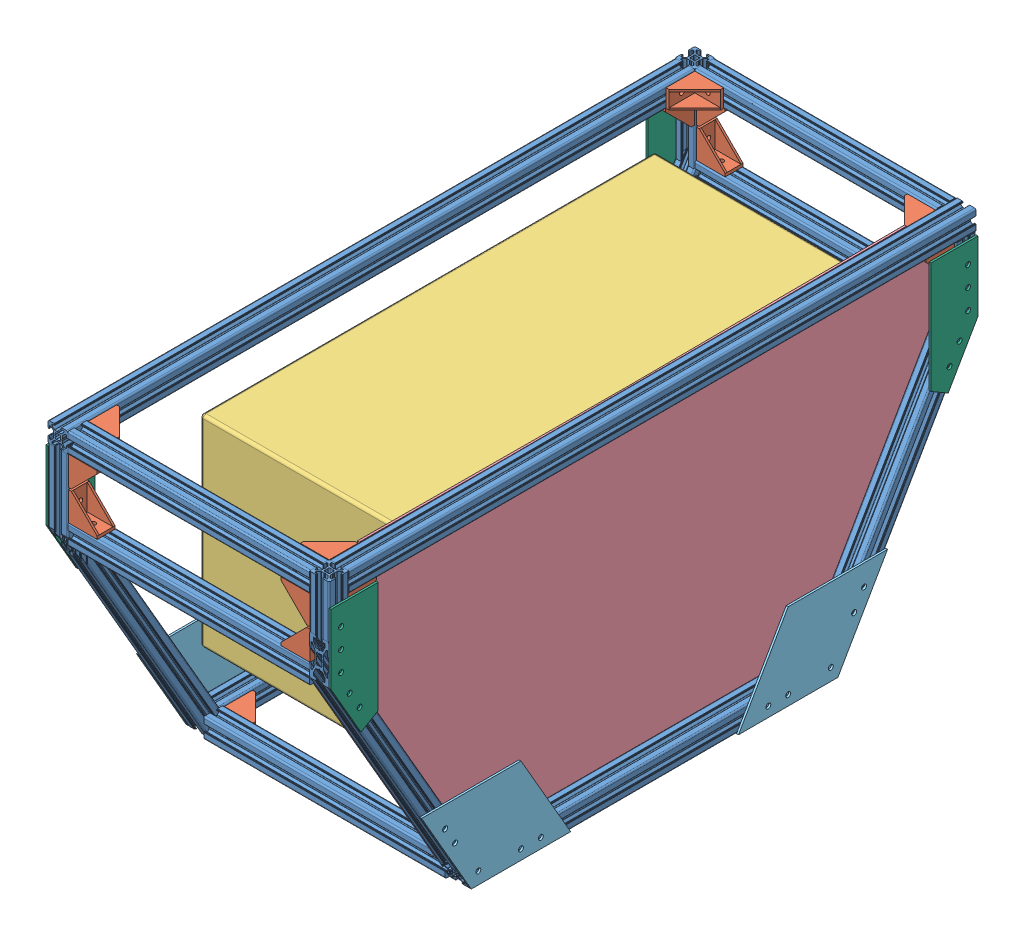
SolidWorks assembly FC, configuration Default. Lengths in mm.
Overall size (287 385.78 744.01).
43 component instances, 9 part files, 122 mates.
Components (placement in the parent):
- Front Compartment Chassis-1: Front Compartment Chassis [Default<As Machined>] at (339.5187 321.3389 505.6666) size (283 336.94 651)
- L- Bracket-1: L- Bracket [Default] at (86.5177 199.1423 674.3681) x (0 1 0) z (-1 0 0) size (18 29 29)
- L- Bracket-2: L- Bracket [Default] at (86.5177 200.1436 336.9668) x (0 -1 0) z (-1 0 0) size (18 29 29)
- L- Bracket-3: L- Bracket [Default] at (329.5198 200.1418 336.9668) x (0 -1 0) z (0 0 -1) size (18 29 29)
- L- Bracket-4: L- Bracket [Default] at (329.5198 200.1418 674.3681) x (0 1 0) z (0 0 1) size (18 29 29)
- L- Bracket-5: L- Bracket [Default] at (86.5177 446.5855 189.6668) x (0 0 1) z (-1 0 0) size (18 29 29)
- L- Bracket-6: L- Bracket [Default] at (329.5198 446.5855 189.6668) x (0 0 -1) z (1 0 0) size (18 29 29)
- L- Bracket-7: L- Bracket [Default] at (86.5177 446.5855 821.6663) x (0 0 1) z (-1 0 0) size (18 29 29)
- L- Bracket-8: L- Bracket [Default] at (329.5198 446.5855 821.6681) x (0 0 -1) z (1 0 0) size (18 29 29)
- L- Bracket-9: L- Bracket [Default] at (329.5198 506.5877 821.6681) x (0 0 -1) z (0 1 0) size (18 29 29)
- L- Bracket-10: L- Bracket [Default] at (86.5177 506.5877 189.6668) x (0 0 1) z (0 1 0) size (18 29 29)
- L- Bracket-11: L- Bracket [Default] at (339.0177 506.5881 200.165) x (1 0 0) z (0 0 -1) size (18 29 29)
- L- Bracket-12: L- Bracket [Default] at (329.5198 517.0877 811.1681) x (0 1 0) z (0 0 1) size (18 29 29)
- L- Bracket-13: L- Bracket [Default] at (339.0177 506.5881 811.1681) x (1 0 0) z (0 1 0) size (18 29 29)
- L- Bracket-14: L- Bracket [Default] at (329.5198 516.0868 200.1668) x (0 1 0) z (1 0 0) size (18 29 29)
- L- Bracket-15: L- Bracket [Default] at (329.5198 506.5877 189.665) x (0 0 -1) z (0 1 0) size (18 29 29)
- L- Bracket-16: L- Bracket [Default] at (86.5177 516.0855 200.1668) x (0 1 0) z (0 0 -1) size (18 29 29)
- L- Bracket-18: L- Bracket [Default] at (86.5177 516.0855 811.1681) x (0 -1 0) z (0 0 1) size (18 29 29)
- L- Bracket-19: L- Bracket [Default] at (86.5177 506.5877 821.6663) x (0 0 -1) z (-1 0 0) size (18 29 29)
- L- Bracket-20: L- Bracket [Default] at (76.0177 506.5864 811.1663) x (-1 0 0) z (0 0 1) size (18 29 29)
- L- Bracket-23: L- Bracket [Default] at (77.0198 506.5864 200.1668) x (-1 0 0) z (0 1 0) size (18 29 29)
- Payload-2: Payload [Default] at (327.5198 411.615 507.0924) x (0 0 1) z (-1 0 0) size (457.2 208.2 208.2)
- FC Base-1: FC Base [Default] at (327.5198 -0.0183 1010.7565) x (0 0 -1) z (1 0 0) size (639.15 336.88 2)
- FC Shear Plate 2-1: FC Shear Plate 2 [Default] at (64.5198 189.7281 590.188) x (0 0.779319 0.626628) z (1 0 0) size (161.49 93.23 2)
- FC Shear Plate 2-2: FC Shear Plate 2 [Default] at (64.5198 276.2461 272.0032) x (0 -0.153016 0.988224) z (1 0 0) size (161.49 93.23 2)
- FC Shear Plate 2-3: FC Shear Plate 2 [Default] at (349.5177 189.6418 590.1402) x (0 0.779319 0.626628) z (1 0 0) size (161.49 93.23 2)
- FC Shear Plate 2-4: FC Shear Plate 2 [Default] at (351.5177 189.6418 421.1929) x (0 0.779319 -0.626628) z (-1 0 0) size (161.49 93.23 2)
- FC Shear Plate 1-4: FC Shear Plate 1 [Default] at (351.5177 443.907 812.5065) x (0 0.533782 0.845622) z (-1 0 0) size (99.78 112.38 2)
- FC Shear Plate 1-5: FC Shear Plate 1 [Default] at (349.5177 443.907 198.8266) x (0 0.533782 -0.845622) z (1 0 0) size (99.78 112.38 2)
- FC Shear Plate 1-6: FC Shear Plate 1 [Default] at (64.5198 443.9075 198.8283) x (0 0.533782 -0.845622) z (1 0 0) size (99.78 112.38 2)
- FC Shear Plate 1-7: FC Shear Plate 1 [Default] at (66.5198 443.9075 812.5048) x (0 0.533782 0.845622) z (-1 0 0) size (99.78 112.38 2)
- L- Bracket-24: L- Bracket [Default] at (327.5198 418.1739 278.4924) x (0 1 0) z (0 0 1) size (18 29 29)
- L- Bracket-25: L- Bracket [Default] at (327.5198 423.1136 735.6924) x (0 -1 0) z (0 0 -1) size (18 29 29)
- L- Bracket-26: L- Bracket [Default] at (327.5198 310.015 506.1761) x (0 0 -1) z (0 1 0) size (18 29 29)
- Assem1-1: Assem1 [Default] at (297.6727 207.8891 498.6482) x (0 -1 0) z (-1 0 0) (suppressed, hidden)
- l small plate-1: l small plate [Default] at (191.63 189.6407 546.568) x (0 1 0) z (-1 0 0) (suppressed, hidden)
- l small plate-3: l small plate [Default] at (191.63 209.6407 462.5667) x (0 -1 0) z (-1 0 0) (suppressed, hidden)
- big bolt-1: big bolt [Default] at (185.63 199.6407 536.568) x (0 0 -1) z (1 0 0) (suppressed, hidden)
- l small plate-4: l small plate [Default] at (257.6584 209.6429 546.568) x (0 -1 0) z (1 0 0) (suppressed, hidden)
- big bolt-2: big bolt [Default] at (185.63 199.6407 472.5667) x (0 0 -1) z (1 0 0) (suppressed, hidden)
- l small plate-5: l small plate [Default] at (257.6584 189.6429 462.5667) x (0 1 0) z (1 0 0) (suppressed, hidden)
- nut-1: nut [Default] at (198.9295 199.6429 472.5667) x (0 -0.681517 0.731802) z (-1 0 0) (suppressed, hidden)
- nut-2: nut [Default] at (204.9354 199.6429 536.568) x (0 -0.369959 0.929048) z (-1 0 0) (suppressed, hidden)
Mates (geometry in assembly coordinates):
- Coincident386: coincident: plane of assembly; plane of assembly; plane of Front Compartment Chassis-1 through (86.5177 321.3389 505.6666) normal (1 0 0); plane of L- Bracket-1 through (86.5177 190.1423 645.3681) normal (-1 0 0)
- Coincident387: coincident: plane of assembly; plane of assembly; plane of Front Compartment Chassis-1 through (76.5187 208.141 674.3681) normal (0 0 -1); plane of L- Bracket-1 through (86.5177 190.1423 674.3681) normal (0 0 1)
- Coincident388: coincident: line of assembly; line of assembly; line of Front Compartment Chassis-1 through (86.5177 208.1423 310.5137) axis (0 0 1); line of L- Bracket-1 through (86.5177 208.1423 645.3681) axis (0 0 1)
- Coincident389: coincident: plane of assembly; plane of assembly; plane of Front Compartment Chassis-1 through (76.5187 208.141 674.3681) normal (0 0 -1); plane of L- Bracket-4 through (300.5198 191.1418 674.3681) normal (0 0 1)
- Coincident390: coincident: plane of assembly; plane of assembly; plane of Front Compartment Chassis-1 through (329.5198 195.8931 684.3666) normal (-1 0 0); plane of L- Bracket-4 through (329.5198 191.1418 674.3681) normal (1 0 0)
- Coincident391: coincident: line of assembly; line of assembly; line of Front Compartment Chassis-1 through (329.5198 191.1418 691.0062) axis (0 0 -1); line of L- Bracket-4 through (329.5198 191.1418 674.3681) axis (0 0 -1)
- Coincident392: coincident: plane of assembly; plane of assembly; plane of Front Compartment Chassis-1 through (329.5198 195.8931 684.3666) normal (-1 0 0); plane of L- Bracket-3 through (329.5198 209.1418 336.9668) normal (1 0 0)
- Coincident393: coincident: plane of assembly; plane of assembly; plane of Front Compartment Chassis-1 through (76.5187 191.1431 336.9668) normal (0 0 1); plane of L- Bracket-3 through (300.5198 209.1418 336.9668) normal (0 0 -1)
- Coincident394: coincident: line of assembly; line of assembly; line of Front Compartment Chassis-1 through (329.5198 191.1418 691.0062) axis (0 0 -1); line of L- Bracket-3 through (329.5198 191.1418 336.9668) axis (0 0 1)
- Coincident395: coincident: plane of assembly; plane of assembly; plane of Front Compartment Chassis-1 through (86.5177 321.3389 505.6666) normal (1 0 0); plane of L- Bracket-2 through (86.5177 209.1436 365.9668) normal (-1 0 0)
- Coincident396: coincident: plane of assembly; plane of assembly; plane of Front Compartment Chassis-1 through (76.5187 191.1431 336.9668) normal (0 0 1); plane of L- Bracket-2 through (86.5177 209.1436 336.9668) normal (0 0 -1)
- Coincident397: coincident: line of assembly; line of assembly; line of Front Compartment Chassis-1 through (86.5177 191.1436 667.9127) axis (0 0 -1); line of L- Bracket-2 through (86.5177 191.1436 365.9668) axis (0 0 -1)
- Coincident398: coincident: plane of assembly; plane of assembly; plane of Front Compartment Chassis-1 through (76.5187 446.5855 817.4176) normal (0 1 0); plane of L- Bracket-7 through (86.5177 446.5855 812.6663) normal (0 -1 0)
- Coincident399: coincident: plane of assembly; plane of assembly; plane of Front Compartment Chassis-1 through (86.5177 436.5866 812.6663) normal (1 0 0); plane of L- Bracket-7 through (86.5177 475.5855 812.6663) normal (-1 0 0)
- Coincident400: coincident: line of assembly; line of assembly; line of Front Compartment Chassis-1 through (86.5177 401.8668 812.6663) axis (0 1 0); line of L- Bracket-7 through (86.5177 475.5855 812.6663) axis (0 -1 0)
- Coincident401: coincident: plane of assembly; plane of assembly; plane of Front Compartment Chassis-1 through (76.5187 446.5855 817.4176) normal (0 1 0); plane of L- Bracket-8 through (329.5198 446.5855 830.6681) normal (0 -1 0)
- Coincident402: coincident: plane of assembly; plane of assembly; plane of Front Compartment Chassis-1 through (329.5198 516.5866 812.6681) normal (-1 0 0); plane of L- Bracket-8 through (329.5198 475.5855 830.6681) normal (1 0 0)
- Coincident403: coincident: line of assembly; line of assembly; line of Front Compartment Chassis-1 through (86.5177 446.5855 812.6681) axis (1 0 0); line of L- Bracket-8 through (329.5198 446.5855 812.6681) axis (-1 0 0)
- Coincident404: coincident: plane of assembly; plane of assembly; plane of Front Compartment Chassis-1 through (329.5198 516.5866 812.6681) normal (-1 0 0); plane of L- Bracket-9 through (329.5198 506.5877 830.6681) normal (1 0 0)
- Coincident405: coincident: plane of assembly; plane of assembly; plane of Front Compartment Chassis-1 through (76.5187 506.5877 812.6681) normal (0 -1 0); plane of L- Bracket-9 through (300.5198 506.5877 830.6681) normal (0 1 0)
- Coincident406: coincident: line of assembly; line of assembly; line of Front Compartment Chassis-1 through (86.5177 506.5877 812.6681) axis (1 0 0); line of L- Bracket-9 through (300.5198 506.5877 812.6681) axis (1 0 0)
- Coincident407: coincident: plane of assembly; plane of assembly; plane of Front Compartment Chassis-1 through (329.5198 436.5866 198.665) normal (-1 0 0); plane of L- Bracket-6 through (329.5198 475.5855 198.6668) normal (1 0 0)
- Coincident409: coincident: plane of assembly; plane of assembly; plane of Front Compartment Chassis-1 through (76.5187 446.5855 186.4176) normal (0 1 0); plane of L- Bracket-6 through (329.5198 446.5855 198.6668) normal (0 -1 0)
- Coincident410: coincident: line of assembly; line of assembly; line of Front Compartment Chassis-1 through (86.5177 446.5855 198.6668) axis (1 0 0); line of L- Bracket-6 through (329.5198 446.5855 198.6668) axis (-1 0 0)
- Coincident411: coincident: plane of assembly; plane of assembly; plane of Front Compartment Chassis-1 through (86.5177 516.5866 198.6668) normal (1 0 0); plane of L- Bracket-5 through (86.5177 475.5855 180.6668) normal (-1 0 0)
- Coincident412: coincident: plane of assembly; plane of assembly; plane of Front Compartment Chassis-1 through (76.5187 446.5855 198.6668) normal (0 1 0); plane of L- Bracket-5 through (86.5177 446.5855 180.6668) normal (0 -1 0)
- Coincident413: coincident: line of assembly; line of assembly; line of Front Compartment Chassis-1 through (86.5177 446.5855 198.6668) axis (1 0 0); line of L- Bracket-5 through (86.5177 446.5855 198.6668) axis (1 0 0)
- Coincident414: coincident: plane of assembly; plane of assembly; plane of Front Compartment Chassis-1 through (86.5177 516.5866 198.6668) normal (1 0 0); plane of L- Bracket-10 through (86.5177 506.5877 180.6668) normal (-1 0 0)
- Coincident415: coincident: plane of assembly; plane of assembly; plane of Front Compartment Chassis-1 through (76.5187 506.5877 193.9155) normal (0 -1 0); plane of L- Bracket-10 through (115.5177 506.5877 180.6668) normal (0 1 0)
- Coincident416: coincident: line of assembly; line of assembly; line of Front Compartment Chassis-1 through (86.5177 526.5851 198.6668) axis (0 -1 0); line of L- Bracket-10 through (86.5177 506.5877 198.6668) axis (0 -1 0)
- Coincident417: coincident: plane of assembly; plane of assembly; plane of Front Compartment Chassis-1 through (76.5187 520.3355 200.1668) normal (0 0 1); plane of L- Bracket-16 through (115.5177 507.0855 200.1668) normal (0 0 -1)
- Coincident418: coincident: plane of assembly; plane of assembly; plane of Front Compartment Chassis-1 through (86.5177 520.3355 821.1666) normal (1 0 0); plane of L- Bracket-16 through (86.5177 507.0855 200.1668) normal (-1 0 0)
- Coincident419: coincident: line of assembly; line of assembly; line of Front Compartment Chassis-1 through (86.5177 525.0855 200.1668) axis (1 0 0); line of L- Bracket-16 through (115.5177 525.0855 200.1668) axis (-1 0 0)
- Coincident422: coincident: plane of assembly; plane of assembly; plane of Front Compartment Chassis-1 through (76.5187 520.3355 200.1668) normal (0 0 1); plane of L- Bracket-14 through (329.5198 507.0868 200.1668) normal (0 0 -1)
- Coincident423: coincident: plane of assembly; plane of assembly; plane of Front Compartment Chassis-1 through (329.5198 520.3355 190.1666) normal (-1 0 0); plane of L- Bracket-14 through (329.5198 507.0868 229.1668) normal (1 0 0)
- Coincident425: coincident: line of assembly; line of assembly; line of L- Bracket-14 through (329.5198 525.0868 229.1668) axis (0 0 -1); line of Front Compartment Chassis-1 through (329.5198 525.0868 180.1663) axis (0 0 1)
- Coincident426: coincident: plane of assembly; plane of assembly; plane of Front Compartment Chassis-1 through (348.0177 436.5866 200.165) normal (0 0 1); plane of L- Bracket-11 through (330.0177 477.5881 200.165) normal (0 0 -1)
- Coincident427: coincident: plane of assembly; plane of assembly; plane of Front Compartment Chassis-1 through (348.0177 506.5881 190.1666) normal (0 -1 0); plane of L- Bracket-11 through (330.0177 506.5881 200.165) normal (0 1 0)
- Coincident428: coincident: line of assembly; line of assembly; line of Front Compartment Chassis-1 through (348.0177 399.2683 200.165) axis (0 1 0); line of L- Bracket-11 through (348.0177 477.5881 200.165) axis (0 1 0)
- Coincident429: coincident: plane of assembly; plane of assembly; plane of Front Compartment Chassis-1 through (329.5198 436.5866 198.665) normal (-1 0 0); plane of L- Bracket-15 through (329.5198 506.5877 198.665) normal (1 0 0)
- Coincident430: coincident: plane of assembly; plane of assembly; plane of Front Compartment Chassis-1 through (76.5187 506.5877 193.9155) normal (0 -1 0); plane of L- Bracket-15 through (300.5198 506.5877 198.665) normal (0 1 0)
- Coincident431: coincident: line of assembly; line of assembly; line of Front Compartment Chassis-1 through (329.5198 401.8664 198.665) axis (0 1 0); line of L- Bracket-15 through (329.5198 506.5877 198.665) axis (0 -1 0)
- Coincident432: coincident: plane of assembly; plane of assembly; plane of Front Compartment Chassis-1 through (335.7698 516.5866 811.1681) normal (0 0 -1); plane of L- Bracket-13 through (330.0177 506.5881 811.1681) normal (0 0 1)
- Coincident433: coincident: plane of assembly; plane of assembly; plane of Front Compartment Chassis-1 through (335.7698 506.5881 190.1666) normal (0 -1 0); plane of L- Bracket-13 through (330.0177 506.5881 782.1681) normal (0 1 0)
- Coincident434: coincident: line of assembly; plane of assembly; line of Front Compartment Chassis-1 through (348.0177 526.5868 811.1681) axis (0 -1 0); plane of L- Bracket-13 through (348.0177 506.5881 811.1681) normal (1 0 0)
- Coincident435: coincident: plane of assembly; plane of assembly; plane of Front Compartment Chassis-1 through (329.5198 508.0881 190.1666) normal (-1 0 0); plane of L- Bracket-12 through (329.5198 508.0877 811.1681) normal (1 0 0)
- Coincident436: coincident: line of assembly; line of assembly; line of Front Compartment Chassis-1 through (86.5177 508.0877 811.1681) axis (1 0 0); line of L- Bracket-12 through (300.5198 508.0877 811.1681) axis (1 0 0)
- Coincident437: coincident: plane of assembly; plane of assembly; plane of Front Compartment Chassis-1 through (80.2677 506.5864 821.1666) normal (0 -1 0); plane of L- Bracket-20 through (85.0177 506.5864 811.1663) normal (0 1 0)
- Coincident438: coincident: plane of assembly; plane of assembly; plane of Front Compartment Chassis-1 through (68.0198 436.5866 811.1663) normal (0 0 -1); plane of L- Bracket-20 through (85.0177 477.5864 811.1663) normal (0 0 1)
- Coincident439: coincident: line of assembly; line of assembly; line of Front Compartment Chassis-1 through (85.0177 399.2688 811.1663) axis (0 1 0); line of L- Bracket-20 through (85.0177 477.5864 811.1663) axis (0 1 0)
- Coincident440: coincident: plane of assembly; plane of assembly; plane of Front Compartment Chassis-1 through (86.5177 508.0864 821.1666) normal (1 0 0); plane of L- Bracket-18 through (86.5177 525.0855 811.1681) normal (-1 0 0)
- Coincident441: coincident: plane of assembly; plane of assembly; plane of Front Compartment Chassis-1 through (76.5187 525.0855 811.1681) normal (0 0 -1); plane of L- Bracket-18 through (115.5177 525.0855 811.1681) normal (0 0 1)
- Coincident442: coincident: plane of assembly; plane of assembly; plane of Front Compartment Chassis-1 through (76.5187 506.5877 824.9155) normal (0 -1 0); plane of L- Bracket-19 through (86.5177 506.5877 830.6663) normal (0 1 0)
- Coincident443: coincident: plane of assembly; plane of assembly; plane of Front Compartment Chassis-1 through (86.5177 436.5866 812.6663) normal (1 0 0); plane of L- Bracket-19 through (86.5177 477.5877 830.6663) normal (-1 0 0)
- Coincident445: coincident: line of assembly; line of assembly; line of Front Compartment Chassis-1 through (86.5177 525.0855 811.1681) axis (1 0 0); line of L- Bracket-18 through (115.5177 525.0855 811.1681) axis (-1 0 0)
- Coincident446: coincident: line of assembly; line of assembly; line of Front Compartment Chassis-1 through (86.5177 401.8668 812.6663) axis (0 1 0); line of L- Bracket-19 through (86.5177 477.5877 812.6663) axis (0 1 0)
- Coincident447: coincident: plane of assembly; plane of assembly; plane of Front Compartment Chassis-1 through (68.0198 506.5864 821.1666) normal (0 -1 0); plane of L- Bracket-23 through (86.0198 506.5864 229.1668) normal (0 1 0)
- Coincident448: coincident: plane of assembly; plane of assembly; plane of Front Compartment Chassis-1 through (68.0198 516.5866 200.1668) normal (0 0 1); plane of L- Bracket-23 through (86.0198 506.5864 200.1668) normal (0 0 -1)
- Coincident449: coincident: line of assembly; line of assembly; line of Front Compartment Chassis-1 through (68.0198 506.5864 831.165) axis (0 0 -1); line of L- Bracket-23 through (68.0198 506.5864 229.1668) axis (0 0 -1)
- Coincident453: coincident: plane of assembly; plane of assembly; plane of Front Compartment Chassis-1 through (76.5187 525.0855 811.1681) normal (0 0 -1); plane of L- Bracket-12 through (300.5198 508.0877 811.1681) normal (0 0 1)
- Coincident457: coincident: plane of assembly; plane of assembly; plane of Front Compartment Chassis-1 through (329.5198 195.8931 684.3666) normal (-1 0 0); plane of FC Base-1 through (329.5198 -0.0183 1010.7565) normal (1 0 0)
- Parallel27: parallel: plane of assembly; plane of assembly; plane of L- Bracket-3 through (326.5198 209.1418 365.9668) normal (0 0 1); plane of FC Base-1 through (329.5198 210.0887 367.2409) normal (0 0 -1)
- Parallel28: parallel: plane of assembly; plane of assembly; plane of Front Compartment Chassis-1 through (331.0198 189.6418 684.3666) normal (0 -1 0); plane of FC Base-1 through (329.5198 189.5587 643.4624) normal (0 -1 0)
- Lock117: lock: unknown of Front Compartment Chassis-1; unknown of FC Base-1
- Coincident462: coincident: plane of assembly; plane of assembly; plane of Front Compartment Chassis-1 through (66.5198 195.3928 691.7264) normal (-1 0 0); plane of FC Shear Plate 2-1 through (66.5198 189.7281 590.188) normal (1 0 0)
- Parallel31: parallel: plane of assembly; plane of assembly; plane of Front Compartment Chassis-1 through (85.0177 189.6436 326.9666) normal (0 -1 0); plane of FC Shear Plate 2-1 through (66.5198 189.7281 590.188) normal (0 -1 0)
- Coincident464: coincident: plane of assembly; plane of assembly; plane of Front Compartment Chassis-1 through (72.7698 194.6428 693.0255) normal (0 -0.5 0.866025); plane of FC Shear Plate 2-1 through (66.5198 189.7281 690.188) normal (0 -0.5 0.866025)
- Lock119: lock: unknown of Front Compartment Chassis-1; unknown of FC Shear Plate 2-1
- Coincident466: coincident: plane of assembly; plane of assembly; plane of Front Compartment Chassis-1 through (66.5198 432.3374 182.8067) normal (-1 0 0); plane of FC Shear Plate 2-2 through (66.5198 276.2461 272.0032) normal (1 0 0)
- Coincident468: coincident: plane of assembly; plane of assembly; plane of Front Compartment Chassis-1 through (85.0177 189.6436 326.9666) normal (0 -1 0); plane of FC Shear Plate 2-2 through (66.5198 189.6436 322.0032) normal (0 -1 0)
- Lock120: lock: unknown of Front Compartment Chassis-1; unknown of FC Shear Plate 2-2
- Coincident470: coincident: plane of assembly; plane of assembly; plane of Front Compartment Chassis-1 through (349.5177 203.391 684.3666) normal (1 0 0); plane of FC Shear Plate 2-3 through (349.5177 189.6418 590.1402) normal (-1 0 0)
- Coincident471: coincident: plane of assembly; plane of assembly; plane of FC Shear Plate 2-3 through (351.5177 189.6418 690.1402) normal (0 -0.5 0.866025); plane of Front Compartment Chassis-1 through (343.2677 431.5865 829.827) normal (0 -0.5 0.866025)
- Coincident472: coincident: plane of assembly; plane of assembly; plane of Front Compartment Chassis-1 through (343.2677 189.6418 684.3666) normal (0 -1 0); plane of FC Shear Plate 2-3 through (351.5177 189.6418 590.1402) normal (0 -1 0)
- Coincident473: coincident: plane of assembly; plane of assembly; plane of Front Compartment Chassis-1 through (349.5177 191.1418 684.3666) normal (1 0 0); plane of FC Shear Plate 2-4 through (349.5177 189.6418 421.1929) normal (-1 0 0)
- Coincident474: coincident: plane of assembly; plane of assembly; plane of Front Compartment Chassis-1 through (343.2677 189.6418 684.3666) normal (0 -1 0); plane of FC Shear Plate 2-4 through (349.5177 189.6418 421.1929) normal (0 -1 0)
- Coincident475: coincident: plane of assembly; plane of assembly; plane of Front Compartment Chassis-1 through (343.2677 194.6419 318.3061) normal (0 -0.5 -0.866025); plane of FC Shear Plate 2-4 through (349.5177 189.6418 321.1929) normal (0 -0.5 -0.866025)
- Coincident476: coincident: plane of assembly; plane of assembly; plane of Front Compartment Chassis-1 through (349.5177 516.5866 829.6668) normal (1 0 0); plane of FC Shear Plate 1-4 through (349.5177 443.907 812.5065) normal (-1 0 0)
- Coincident477: coincident: plane of assembly; plane of assembly; plane of Front Compartment Chassis-1 through (343.2677 431.5865 829.827) normal (0 -0.5 0.866025); plane of FC Shear Plate 1-4 through (349.5177 433.907 831.1668) normal (0 -0.5 0.866025)
- Coincident478: coincident: plane of assembly; plane of assembly; plane of Front Compartment Chassis-1 through (331.0198 516.5866 831.1668) normal (0 0 1); plane of FC Shear Plate 1-4 through (349.5177 503.907 831.1668) normal (0 0 1)
- Coincident479: coincident: plane of assembly; plane of assembly; plane of Front Compartment Chassis-1 through (349.5177 436.5866 181.6663) normal (1 0 0); plane of FC Shear Plate 1-5 through (349.5177 443.907 198.8266) normal (-1 0 0)
- Coincident480: coincident: plane of assembly; plane of assembly; plane of Front Compartment Chassis-1 through (343.2677 436.5866 180.1663) normal (0 0 -1); plane of FC Shear Plate 1-5 through (351.5177 503.907 180.1663) normal (0 0 -1)
- Coincident481: coincident: plane of assembly; plane of assembly; plane of Front Compartment Chassis-1 through (343.2677 194.6419 318.3061) normal (0 -0.5 -0.866025); plane of FC Shear Plate 1-5 through (351.5177 433.907 180.1663) normal (0 -0.5 -0.866025)
- Coincident482: coincident: plane of assembly; plane of assembly; plane of Front Compartment Chassis-1 through (66.5198 201.5165 681.1199) normal (-1 0 0); plane of FC Shear Plate 1-7 through (66.5198 443.9075 812.5048) normal (1 0 0)
- Coincident483: coincident: plane of assembly; plane of assembly; plane of Front Compartment Chassis-1 through (72.7698 436.5866 831.165) normal (0 0 1); plane of FC Shear Plate 1-7 through (64.5198 503.9075 831.165) normal (0 0 1)
- Coincident484: coincident: plane of assembly; plane of assembly; plane of Front Compartment Chassis-1 through (72.7698 194.6428 693.0255) normal (0 -0.5 0.866025); plane of FC Shear Plate 1-7 through (64.5198 433.9075 831.165) normal (0 -0.5 0.866025)
- Coincident485: coincident: plane of assembly; plane of assembly; plane of Front Compartment Chassis-1 through (66.5198 438.4611 193.4132) normal (-1 0 0); plane of FC Shear Plate 1-6 through (66.5198 443.9075 198.8283) normal (1 0 0)
- Coincident486: coincident: plane of assembly; plane of assembly; plane of Front Compartment Chassis-1 through (72.7698 431.5874 181.5076) normal (0 -0.5 -0.866025); plane of FC Shear Plate 1-6 through (66.5198 433.9075 180.1681) normal (0 -0.5 -0.866025)
- Coincident487: coincident: plane of assembly; plane of assembly; plane of Front Compartment Chassis-1 through (72.7698 516.5866 180.1681) normal (0 0 -1); plane of FC Shear Plate 1-6 through (66.5198 503.9075 180.1681) normal (0 0 -1)
- Coincident491: coincident: plane of assembly; plane of assembly; plane of Payload-2 through (327.5198 411.615 507.0924) normal (1 0 0); plane of FC Base-1 through (327.5198 -0.0183 1010.7565) normal (-1 0 0)
- Lock122: lock: unknown of Payload-2; unknown of FC Base-1
- Coincident492: coincident: plane of assembly; plane of assembly; plane of FC Base-1 through (327.5198 -0.0183 1010.7565) normal (-1 0 0); plane of L- Bracket-24 through (327.5198 409.1739 278.4924) normal (1 0 0)
- Coincident493: coincident: plane of assembly; plane of assembly; plane of Payload-2 through (124.3198 310.015 278.4924) normal (0 0 -1); plane of L- Bracket-24 through (298.5198 409.1739 278.4924) normal (0 0 1)
- Lock123: lock: unknown of Payload-2; unknown of L- Bracket-24
- Coincident495: coincident: plane of assembly; plane of assembly; plane of FC Base-1 through (327.5198 -0.0183 1010.7565) normal (-1 0 0); plane of L- Bracket-26 through (327.5198 310.015 515.1761) normal (1 0 0)
- Coincident496: coincident: plane of assembly; plane of assembly; plane of Payload-2 through (124.3198 310.015 278.4924) normal (0 -1 0); plane of L- Bracket-26 through (298.5198 310.015 515.1761) normal (0 1 0)
- Lock124: lock: unknown of Payload-2; unknown of L- Bracket-26
- Coincident498: coincident: plane of assembly; plane of assembly; plane of FC Base-1 through (327.5198 -0.0183 1010.7565) normal (-1 0 0); plane of L- Bracket-25 through (327.5198 432.1136 735.6924) normal (1 0 0)
- Coincident499: coincident: plane of assembly; plane of assembly; plane of Payload-2 through (124.3198 310.015 735.6924) normal (0 0 1); plane of L- Bracket-25 through (298.5198 432.1136 735.6924) normal (0 0 -1)
- Lock125: lock: unknown of Payload-2; unknown of L- Bracket-25
- Coincident500: coincident: plane of Front Compartment Chassis-1 through (86.5177 189.6429 560.3171) normal (0 -1 0); plane of ? through (170.018 189.6429 546.568) normal (0 1 0)
- Coincident503: coincident: plane of Front Compartment Chassis-1 through (86.5177 195.8929 442.568) normal (0 0 -1); plane of ? through (170.018 169.6429 442.568) normal (0 0 -1)
- Lock126: lock: unknown of Front Compartment Chassis-1; unknown of ?
- Coincident505: coincident: plane of assembly; plane of assembly; plane of Front Compartment Chassis-1 through (86.5177 195.8929 546.568) normal (0 0 -1); plane of l small plate-1 through (189.63 189.6407 546.568) normal (0 0 1)
- Parallel34: parallel: plane of assembly; plane of assembly; plane of FC Base-1 through (327.5198 -0.0183 1010.7565) normal (-1 0 0); plane of l small plate-1 through (191.63 189.6407 546.568) normal (1 0 0)
- Coincident510: coincident: plane of assembly; plane of assembly; plane of l small plate-1 through (169.63 189.6407 546.568) normal (-1 0 0); plane of l small plate-3 through (169.63 209.6407 462.5667) normal (-1 0 0)
- Coincident512: coincident: plane of assembly; plane of assembly; plane of Front Compartment Chassis-1 through (86.5177 203.3907 462.5667) normal (0 0 1); plane of l small plate-3 through (189.63 209.6407 462.5667) normal (0 0 -1)
- Parallel36: parallel: plane of assembly; plane of assembly; plane of l small plate-1 through (189.63 189.6407 526.568) normal (0 0 -1); plane of l small plate-3 through (189.63 209.6407 482.5667) normal (0 0 1)
- Concentric1: concentric: circle of assembly; circle of assembly; circle of l small plate-1; circle of l small plate-3
- Coincident516: coincident: plane of assembly; plane of assembly; plane of Front Compartment Chassis-1 through (86.5177 209.6407 552.8193) normal (0 1 0); plane of l small plate-1 through (189.63 209.6407 546.568) normal (0 1 0)
- Coincident517: coincident: circle of assembly; circle of assembly; circle of l small plate-1; circle of big bolt-1
- Coincident518: coincident: plane of assembly; plane of assembly; plane of Front Compartment Chassis-1 through (86.5177 195.8929 546.568) normal (0 0 -1); plane of l small plate-4 through (259.6584 209.6429 546.568) normal (0 0 1)
- Parallel37: parallel: plane of assembly; plane of assembly; plane of Front Compartment Chassis-1 through (86.5177 189.6429 548.068) normal (0 -1 0); plane of l small plate-4 through (259.6584 209.6429 546.568) normal (0 1 0)
- Coincident520: coincident: plane of assembly; plane of assembly; plane of Front Compartment Chassis-1 through (86.5177 189.6429 548.068) normal (0 -1 0); plane of l small plate-4 through (259.6584 189.6429 546.568) normal (0 -1 0)
- Coincident521: coincident: circle of assembly; circle of assembly; circle of l small plate-3; circle of big bolt-2
- Lock127: lock: unknown of Front Compartment Chassis-1; unknown of l small plate-4
- Concentric3: concentric: circle of assembly; circle of assembly; circle of l small plate-4; circle of l small plate-5
- Coincident528: coincident: plane of assembly; plane of assembly; plane of Front Compartment Chassis-1 through (86.5177 191.1429 462.5667) normal (0 0 1); plane of l small plate-5 through (259.6584 189.6429 462.5667) normal (0 0 -1)
- Parallel40: parallel: plane of assembly; plane of assembly; plane of l small plate-4 through (259.6584 209.6429 526.568) normal (0 0 -1); plane of l small plate-5 through (259.6584 189.6429 482.5667) normal (0 0 1)
- Coincident530: coincident: plane of assembly; plane of assembly; plane of Front Compartment Chassis-1 through (86.5177 189.6429 456.3171) normal (0 -1 0); plane of l small plate-5 through (259.6584 189.6429 462.5667) normal (0 -1 0)
- Concentric4: concentric: circle of assembly; circle of assembly; circle of l small plate-5; circle of nut-1
- Concentric5: concentric: circle of assembly; circle of assembly; circle of l small plate-4; circle of nut-2
